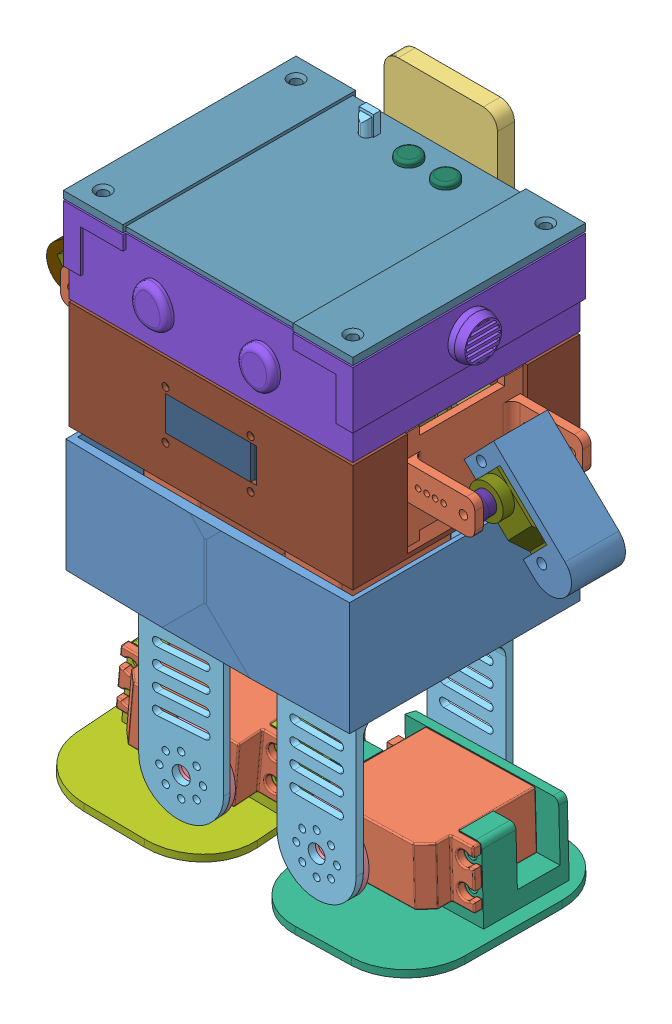
SolidWorks assembly Assemblage1, configuration Défaut. Lengths in mm.
Overall size (196.1 206.73 109.28).
35 component instances, 23 part files, 95 mates.
Components (placement in the parent):
- BodyBase-1: BodyBase [Défaut] at (-19.3328 -12.673 140) size (100 40 82)
- ServoS1213-1: ServoS1213 [Défaut] at (15.6672 25.827 129) x (0 0 -1) z (0 1 0) size (55 20 44)
- ServoS1213-2: ServoS1213 [Défaut] at (65.4301 25.827 129.0817) x (0.005444 0 -0.999985) z (0 1 0) size (55 20 44)
- LSM303D-1: LSM303D [Défaut] at (37.1672 -5.173 110) x (0 0 -1) z (0 1 0) size (21 13 13)
- PalonnierS1213-1: PalonnierS1213 [Défaut] at (5.6672 -20.173 100) x (0.070882 0 0.997485) z (-0.997485 0 0.070882) size (28 6 28)
- PalonnierS1213-2: PalonnierS1213 [Défaut] at (55.5882 -20.173 100.0277) x (0.710492 0 -0.703705) z (0.703705 0 0.710492) size (28 6 28)
- Bracket-1: Bracket [Défaut] at (69.72 -20.173 72.5952) x (-0.004799 0 0.999988) z (0.999988 0 0.004799) size (55 62.5 28)
- Bracket-2: Bracket [Défaut] at (17.6827 -20.173 71.5768) x (0.070882 0 0.997485) z (0.997485 0 -0.070882) size (55 62.5 28)
- Pied-1: Pied [Défaut] at (38.2903 -87.6714 63.4443) x (-0.004799 0 0.999988) z (-0.999594 -0.028092 -0.004797) size (74 28.5 60)
- ServoS1213-3: ServoS1213 [Défaut] at (84.9581 -77.8544 79.1684) x (-0.999594 -0.028092 -0.004797) z (0.004799 0 -0.999988) size (55 20 44)
- ServoS1213-4: ServoS1213 [Défaut] at (-23.7938 -56.2397 81.0406) x (0.993861 -0.085163 -0.070624) z (-0.070882 0 -0.997485) size (55 20 44)
- PalonnierS1213-3: PalonnierS1213 [Défaut] at (7.4392 -68.673 124.9371) x (0.705328 -0.707107 -0.050121) z (0.705328 0.707107 -0.050121) size (28 6 28)
- PalonnierS1213-4: PalonnierS1213 [Défaut] at (55.4682 -68.673 125.0274) x (0.999988 0 0.004799) z (0 1 0) size (28 6 28)
- Pied - Copie-1: Pied - Copie [Défaut] at (-40.2337 -83.529 66.6697) x (0.070882 0 0.997485) z (-0.993861 0.085163 0.070624) size (74 28.5 60)
- BodyMiddle-1: BodyMiddle [Défaut] at (-19.3328 69.5099 140) size (112 31.5 84)
- SocleBat-1: SocleBat [Défaut] at (-12.8328 70.5099 100) size (70 21 25)
- SocleBat-2: SocleBat [Défaut] at (-12.8328 70.5099 127) size (70 21 25)
- Ecran-1: Ecran [Défaut] at (12.6672 40.5959 135.5) x (1 0 0) z (0 -1 0) size (34 4.5 21)
- BodyTop-1: BodyTop [Défaut] at (-19.3328 30.5959 140) size (100 39.5 80)
- Teensy-bras-corps-base-X4-1: Teensy-bras-corps-base-X4 [Défaut] at (44.1672 32.0959 100.4183) x (0 0 1) z (0 1 0) size (45 57 25)
- PololuMicroMeastro-1: PololuMicroMeastro [Défaut] at (0.8991 32.0959 88.8193) x (0 0 -1) z (0 1 0) size (32.11 21.5 9.5)
- Couvercle-1: Couvercle [Défaut] at (-20.3328 100.1095 140) size (102 4 82)
- AttacheP-1: AttacheP [Défaut] at (43.161 101.6095 69.7544) x (0.425281 0 0.905062) z (-0.905062 0 0.425281) size (20 5.2 8)
- AttacheP-3: AttacheP [Défaut] at (29.9227 101.6095 69.5261) x (-0.997758 0 0.066931) z (-0.066931 0 -0.997758) size (20 5.2 8)
- ServoS1123-1: ServoS1123 [Défaut] at (-29.9448 51.815 86) x (-0.805744 -0.592264 0) z (0 0 -1) size (33 12 29)
- ServoS1123-2: ServoS1123 [Défaut] at (99.5187 61.5799 86) x (0.719374 -0.694623 0) z (0 0 -1) size (33 12 29)
- PalonnierS1123-1: PalonnierS1123 [Défaut] at (-38.3328 53.0959 117) x (1 0 0) z (0 1 0) size (22.5 5 8)
- PalonnierS1123-2: PalonnierS1123 [Défaut] at (99.6672 53.0959 117) x (-1 0 0) z (0 -1 0) size (22.5 5 8)
- MainD-1: MainD [Défaut] at (-53.3113 34.6394 83) x (0.805744 0.592264 0) z (0.592264 -0.805744 0) size (42.5 22 15)
- MainG-2: MainG [Défaut] at (86.867 57.1152 88) x (0.719374 -0.694623 0) z (-0.694623 -0.719374 0) size (42.5 22 15)
- epaule-1: epaule [Défaut] at (-14.8328 32.0959 75.5) x (0 0 1) z (-1 0 0) size (48 35 27.5)
- epaule-2: epaule [Défaut] at (76.1672 32.0959 123.5) x (0 0 -1) z (1 0 0) size (48 35 27.5)
- telecommande-1: telecommande [Défaut] at (48.6672 33.0959 51) x (0 1 0) z (0 0 1) size (85 40 7)
- sac-1: sac [Défaut] at (55.6672 30.0959 48) x (0 0 1) z (0 -1 0) size (31.28 50.4 43.75)
- ReceptIR-1: ReceptIR [Défaut] at (12.1672 101.6095 66.75) x (1 0 0) z (0 -1 0) size (5 4.5 30)
Mates (geometry in assembly coordinates):
- Coaxiale1: concentric aligned: circle of BodyBase-1; circle of ServoS1213-2
- Coïncidente2: coincident anti-aligned: plane of BodyBase-1 through (-19.3328 -4.173 140) normal (0 1 0); plane of ServoS1213-2 through (65.686 -4.173 82.0824) normal (0 -1 0)
- Coaxiale5: concentric anti-aligned: circle of BodyBase-1; circle of ServoS1213-2
- Coaxiale6: concentric aligned: circle of BodyBase-1; circle of ServoS1213-1
- Coïncidente3: coincident anti-aligned: plane of BodyBase-1 through (-19.3328 -4.173 140) normal (0 1 0); plane of ServoS1213-1 through (15.6672 -4.173 82) normal (0 -1 0)
- Coaxiale9: concentric aligned: circle of BodyBase-1; circle of ServoS1213-1
- Coïncidente4: coincident anti-aligned: plane of BodyBase-1 through (-19.3328 -5.173 140) normal (0 1 0); plane of LSM303D-1 through (37.1672 -5.173 110) normal (0 -1 0)
- Coïncidente5: coincident aligned: cylinder of BodyBase-1 through (34.6672 -19.173 107.5) axis (0 1 0) radius 1.25; circle of LSM303D-1
- Parallèle1: parallel anti-aligned: plane of BodyBase-1 through (37.1672 -5.173 94) normal (-1 0 0); plane of LSM303D-1 through (37.1672 -3.173 110) normal (1 0 0)
- Coaxiale10: concentric anti-aligned: circle of ServoS1213-1; circle of PalonnierS1213-1
- Coaxiale12: concentric anti-aligned: circle of ServoS1213-2; circle of PalonnierS1213-2
- Coïncidente7: coincident anti-aligned: plane of ServoS1213-2 through (55.5882 -18.173 100.0277) normal (0 -1 0); plane of PalonnierS1213-2 through (55.5882 -18.173 100.0277) normal (0 1 0)
- Coïncidente8: coincident anti-aligned: plane of ServoS1213-1 through (5.6672 -18.173 100) normal (0 -1 0); circle of PalonnierS1213-1
- Coaxiale13: concentric anti-aligned: circle of PalonnierS1213-1; circle of Bracket-2
- Coïncidente9: coincident anti-aligned: plane of PalonnierS1213-1 through (5.6672 -20.173 100) normal (0 -1 0); plane of Bracket-2 through (17.6827 -20.173 71.5768) normal (0 1 0)
- Coaxiale14: concentric anti-aligned: circle of PalonnierS1213-1; circle of Bracket-2
- Coïncidente10: coincident anti-aligned: plane of PalonnierS1213-2 through (55.5882 -20.173 100.0277) normal (0 -1 0); plane of Bracket-1 through (69.72 -20.173 72.5952) normal (0 1 0)
- Coaxiale15: concentric anti-aligned: circle of PalonnierS1213-2; circle of Bracket-1
- Coaxiale16: concentric anti-aligned: circle of PalonnierS1213-2; circle of Bracket-1
- Coaxiale17: concentric aligned: circle of Pied-1; cylinder of ServoS1213-3 through (88.9293 -62.734 101.1877) axis (-0.004799 0 0.999988) radius 2.5
- Coaxiale18: concentric aligned: circle of Pied-1; cylinder of ServoS1213-3 through (41.2297 -74.0784 100.9588) axis (-0.004799 0 0.999988) radius 2.5
- Coïncidente11: coincident anti-aligned: plane of Pied-1 through (92.8253 -77.6297 106.2065) normal (-0.004799 0 0.999988); plane of ServoS1213-3 through (37.8476 -79.1747 105.9426) normal (0.004799 0 -0.999988)
- Coaxiale19: concentric aligned: cylinder of ServoS1213-3 through (55.4778 -68.673 123.0275) axis (0.004799 0 -0.999988) radius 3; cylinder of PalonnierS1213-4 through (55.4778 -68.673 123.0275) axis (0.004799 0 -0.999988) radius 3.0436
- Coïncidente12: coincident anti-aligned: plane of ServoS1213-3 through (55.4778 -68.673 123.0275) normal (-0.004799 0 0.999988); plane of PalonnierS1213-4 through (55.4778 -68.673 123.0275) normal (0.004799 0 -0.999988)
- Coaxiale20: concentric aligned: circle of Bracket-1; circle of PalonnierS1213-4
- Coaxiale21: concentric anti-aligned: circle of Bracket-1; circle of PalonnierS1213-4
- Coïncidente14: coincident anti-aligned: plane of Bracket-1 through (41.4684 -82.673 124.9602) normal (0.004799 0 -0.999988); plane of PalonnierS1213-4 through (55.4682 -68.673 125.0274) normal (-0.004799 0 0.999988)
- Coaxiale22: concentric anti-aligned: circle of Bracket-1; circle of Pied-1
- Coaxiale23: concentric anti-aligned: circle of ServoS1213-4; circle of Pied - Copie-1
- Coaxiale24: concentric aligned: circle of ServoS1213-4; circle of Pied - Copie-1
- Coïncidente15: coincident anti-aligned: plane of ServoS1213-4 through (24.8315 -60.2423 104.6533) normal (-0.070882 0 -0.997485); plane of Pied - Copie-1 through (23.1325 -80.1696 104.774) normal (0.070882 0 0.997485)
- Coaxiale25: concentric aligned: cylinder of Bracket-2 through (3.7179 -68.673 72.5692) axis (0.070882 0 0.997485) radius 3; cylinder of Pied - Copie-1 through (3.6116 -68.673 71.0729) axis (0.070882 0 0.997485) radius 2.95
- Coaxiale26: concentric aligned: cylinder of ServoS1213-4 through (7.2975 -68.673 122.9421) axis (-0.070882 0 -0.997485) radius 3; cylinder of PalonnierS1213-3 through (7.2975 -68.673 122.9421) axis (-0.070882 0 -0.997485) radius 3.0436
- Coïncidente16: coincident anti-aligned: plane of ServoS1213-4 through (7.2975 -68.673 122.9421) normal (0.070882 0 0.997485); plane of PalonnierS1213-3 through (7.2975 -68.673 122.9421) normal (-0.070882 0 -0.997485)
- Coaxiale29: concentric anti-aligned: circle of Bracket-2; circle of PalonnierS1213-3
- Coaxiale30: concentric anti-aligned: circle of Bracket-2; circle of PalonnierS1213-3
- Coïncidente22: coincident anti-aligned: plane of Bracket-2 through (-6.5256 -82.673 125.9295) normal (-0.070882 0 -0.997485); plane of PalonnierS1213-3 through (7.4392 -68.673 124.9371) normal (0.070882 0 0.997485)
- Coaxiale31: concentric aligned: circle of Pied-1; cylinder of ServoS1213-3 through (40.9488 -64.0823 100.9575) axis (-0.004799 0 0.999988) radius 2.5
- Coaxiale32: concentric aligned: circle of Pied-1; circle of ServoS1213-3
- Coïncidente24: coincident anti-aligned: circle of BodyBase-1; cylinder of BodyMiddle-1 through (74.6672 64.5099 134) axis (0 1 0) radius 1.75
- Coaxiale33: concentric aligned: cylinder of BodyBase-1 through (-13.3328 -19.173 66) axis (0 1 0) radius 1.75; cylinder of BodyMiddle-1 through (-13.3328 64.5099 66) axis (0 1 0) radius 1.75
- Coïncidente28: coincident anti-aligned: plane of BodyMiddle-1 through (-19.3328 70.5099 140) normal (0 1 0); plane of SocleBat-2 through (-12.8328 70.5099 127) normal (0 -1 0)
- Coïncidente29: coincident anti-aligned: plane of BodyMiddle-1 through (-19.3328 70.5099 140) normal (0 1 0); plane of SocleBat-1 through (-12.8328 70.5099 100) normal (0 -1 0)
- Coïncidente30: coincident anti-aligned: plane of BodyMiddle-1 through (57.1672 70.5099 107) normal (-1 0 0); plane of SocleBat-2 through (57.1672 91.5099 127) normal (1 0 0)
- Coïncidente32: coincident anti-aligned: plane of BodyMiddle-1 through (57.1672 70.5099 80) normal (-1 0 0); plane of SocleBat-1 through (57.1672 91.5099 100) normal (1 0 0)
- Coïncidente33: coincident anti-aligned: plane of BodyMiddle-1 through (57.1672 70.5099 100) normal (0 0 -1); plane of SocleBat-1 through (-12.8328 91.5099 100) normal (0 0 1)
- Coaxiale36: concentric anti-aligned: cylinder of BodyMiddle-1 through (-13.3328 64.5099 66) axis (0 1 0) radius 1.75; cylinder of BodyTop-1 through (-13.3328 32.0959 66) axis (0 -1 0) radius 1.75
- Coaxiale37: concentric anti-aligned: cylinder of BodyMiddle-1 through (74.6672 64.5099 134) axis (0 1 0) radius 1.75; cylinder of BodyTop-1 through (74.6672 32.0959 134) axis (0 -1 0) radius 1.75
- Coïncidente36: coincident anti-aligned: plane of Ecran-1 through (12.6672 40.5959 138.5) normal (0 0 1); plane of BodyTop-1 through (-17.8328 68.5959 138.5) normal (0 0 -1)
- Coaxiale44: concentric aligned: cylinder of Ecran-1 through (44.6672 59.5959 133.5) axis (0 0 1) radius 1.25; cylinder of BodyTop-1 through (44.6672 59.5959 135) axis (0 0 1) radius 1.25
- Coaxiale45: concentric aligned: cylinder of Ecran-1 through (14.6672 42.5959 133.5) axis (0 0 1) radius 1.25; cylinder of BodyTop-1 through (14.6672 42.5959 135) axis (0 0 1) radius 1.25
- Parallèle6: parallel anti-aligned: plane of Couvercle-1 through (-20.3328 101.6095 140) normal (0 1 0); plane of AttacheP-3 through (29.9227 101.6095 69.5261) normal (0 -1 0)
- Parallèle7: parallel anti-aligned: plane of Couvercle-1 through (-20.3328 101.6095 140) normal (0 1 0); plane of AttacheP-1 through (43.161 101.6095 69.7544) normal (0 -1 0)
- Coïncidente45: coincident: circle of Couvercle-1; point of AttacheP-3
- Coïncidente46: coincident: circle of Couvercle-1; point of AttacheP-1
- Coaxiale50: concentric anti-aligned: cylinder of BodyTop-1 through (74.6672 32.0959 134) axis (0 -1 0) radius 1.75; cylinder of Couvercle-1 through (74.6672 96.6095 134) axis (0 1 0) radius 1.75
- Coaxiale51: concentric anti-aligned: cylinder of BodyTop-1 through (-13.3328 32.0959 66) axis (0 -1 0) radius 1.75; cylinder of Couvercle-1 through (-13.3328 96.6095 66) axis (0 1 0) radius 1.75
- Coaxiale52: concentric aligned: cylinder of BodyTop-1 through (68.6672 32.0959 113.9183) axis (0 -1 0) radius 1.75; cylinder of Teensy-bras-corps-base-X4-1 through (68.6672 33.6959 113.9183) axis (0 -1 0) radius 1.6
- Coaxiale53: concentric aligned: cylinder of BodyTop-1 through (19.6672 32.0959 113.9183) axis (0 -1 0) radius 1.75; cylinder of Teensy-bras-corps-base-X4-1 through (19.6672 33.6959 113.9183) axis (0 -1 0) radius 1.6
- Coïncidente47: coincident anti-aligned: plane of BodyTop-1 through (-19.3328 32.0959 140) normal (0 1 0); plane of Teensy-bras-corps-base-X4-1 through (44.1672 32.0959 100.4183) normal (0 -1 0)
- Coaxiale54: concentric aligned: cylinder of BodyTop-1 through (9.3872 32.0959 102.15) axis (0 -1 0) radius 1.25; cylinder of PololuMicroMeastro-1 through (9.3872 33.5959 102.15) axis (0 -1 0) radius 1.25
- Parallèle8: parallel aligned: cylinder of BodyTop-1 through (-7.3328 32.0959 87.64) axis (0 -1 0) radius 1.25; cylinder of PololuMicroMeastro-1 through (-7.3367 33.5959 87.6427) axis (0 -1 0) radius 1.25
- Parallèle10: parallel anti-aligned: plane of BodyTop-1 through (-17.8328 68.5959 61.5) normal (1 0 0); plane of PololuMicroMeastro-1 through (-9.8509 33.5959 88.8193) normal (-1 0 0)
- Coïncidente50: coincident anti-aligned: plane of BodyTop-1 through (-19.3328 32.0959 140) normal (0 1 0); plane of PololuMicroMeastro-1 through (0.8991 32.0959 88.8193) normal (0 -1 0)
- Coaxiale59: concentric anti-aligned: cylinder of ServoS1123-1 through (-38.3328 53.0959 115) axis (0 0 -1) radius 2; cylinder of PalonnierS1123-1 through (-38.3328 53.0959 112) axis (0 0 1) radius 2
- Coïncidente51: coincident anti-aligned: plane of ServoS1123-1 through (-38.3328 53.0959 115) normal (0 0 1); plane of PalonnierS1123-1 through (-38.3328 53.0959 115) normal (0 0 -1)
- Coaxiale60: concentric anti-aligned: cylinder of ServoS1123-2 through (99.6672 53.0959 115) axis (0 0 -1) radius 2; cylinder of PalonnierS1123-2 through (99.6672 53.0959 112) axis (0 0 1) radius 2
- Coïncidente52: coincident anti-aligned: plane of ServoS1123-2 through (99.6672 53.0959 115) normal (0 0 1); plane of PalonnierS1123-2 through (99.6672 53.0959 115) normal (0 0 -1)
- Coaxiale65: concentric aligned: cylinder of ServoS1123-1 through (-30.8394 58.604 99) axis (0 0 1) radius 1.75; cylinder of MainD-1 through (-30.8394 58.604 90) axis (0 0 1) radius 1.75
- Coaxiale68: concentric aligned: cylinder of ServoS1123-1 through (-54.6894 41.073 99) axis (0 0 1) radius 1.75; cylinder of MainD-1 through (-54.6894 41.073 90) axis (0 0 1) radius 1.75
- Coïncidente55: coincident anti-aligned: plane of ServoS1123-1 through (-52.5056 35.2317 102) normal (0 0 -1); plane of MainD-1 through (-57.7533 40.6825 102) normal (0 0 1)
- Coaxiale72: concentric aligned: cylinder of ServoS1123-2 through (114.2705 38.9951 99) axis (0 0 1) radius 1.75; cylinder of MainG-2 through (114.2705 38.9951 95) axis (0 0 1) radius 1.75
- Coaxiale73: concentric aligned: cylinder of ServoS1123-2 through (92.977 59.5559 99) axis (0 0 1) radius 1.75; cylinder of MainG-2 through (92.977 59.5559 95) axis (0 0 1) radius 1.75
- Coïncidente56: coincident anti-aligned: plane of ServoS1123-2 through (119.6611 42.1305 104) normal (0 0 1); plane of MainG-2 through (99.5187 61.5799 104) normal (0 0 -1)
- Parallèle11: parallel anti-aligned: plane of BodyTop-1 through (-17.8328 68.5959 123.5) normal (0 0 -1); plane of epaule-1 through (-17.3328 32.0959 123.5) normal (0 0 1)
- Coïncidente58: coincident anti-aligned: plane of BodyTop-1 through (-19.3328 32.0959 140) normal (0 1 0); plane of epaule-1 through (-17.3328 32.0959 75.5) normal (0 -1 0)
- Coïncidente59: coincident anti-aligned: line of BodyTop-1 through (-14.8328 67.0959 123.5) axis (0 -1 0); line of epaule-1 through (-14.8328 32.0959 123.5) axis (0 1 0)
- Coaxiale74: concentric aligned: cylinder of PalonnierS1123-1 through (-22.3328 53.0959 115) axis (0 0 1) radius 0.75; cylinder of epaule-1 through (-22.3328 53.0959 70) axis (0 0 1) radius 1
- Coaxiale75: concentric aligned: cylinder of PalonnierS1123-1 through (-31.3328 53.0959 115) axis (0 0 1) radius 0.75; cylinder of epaule-1 through (-31.3328 53.0959 70) axis (0 0 1) radius 1
- Coïncidente60: coincident anti-aligned: plane of PalonnierS1123-1 through (-38.3328 53.0959 117) normal (0 0 1); plane of epaule-1 through (-42.3328 59.0959 117) normal (0 0 -1)
- Coïncidente61: coincident anti-aligned: plane of BodyTop-1 through (79.1672 68.5959 75.5) normal (0 0 1); plane of epaule-2 through (78.6672 32.0959 75.5) normal (0 0 -1)
- Coïncidente62: coincident anti-aligned: plane of BodyTop-1 through (-19.3328 32.0959 140) normal (0 1 0); plane of epaule-2 through (78.6672 32.0959 123.5) normal (0 -1 0)
- Coïncidente63: coincident anti-aligned: line of BodyTop-1 through (76.1672 67.0959 75.5) axis (0 -1 0); line of epaule-2 through (76.1672 32.0959 75.5) axis (0 1 0)
- Coaxiale76: concentric anti-aligned: cylinder of PalonnierS1123-2 through (92.6672 53.0959 115) axis (0 0 1) radius 0.75; cylinder of epaule-2 through (92.6672 53.0959 129) axis (0 0 -1) radius 1
- Coaxiale77: concentric anti-aligned: cylinder of PalonnierS1123-2 through (83.6672 53.0959 115) axis (0 0 1) radius 0.75; cylinder of epaule-2 through (83.6672 53.0959 129) axis (0 0 -1) radius 1
- Coïncidente64: coincident anti-aligned: plane of PalonnierS1123-2 through (99.6672 53.0959 117) normal (0 0 1); plane of epaule-2 through (103.6672 59.0959 117) normal (0 0 -1)
- Coïncidente66: coincident anti-aligned: plane of telecommande-1 through (48.6672 33.0959 57) normal (0 -1 0); plane of sac-1 through (5.6672 33.0959 48) normal (0 1 0)
- Coïncidente67: coincident anti-aligned: plane of telecommande-1 through (48.6672 33.0959 57) normal (0 0 1); plane of sac-1 through (5.6672 30.0959 57) normal (0 0 -1)
- Coïncidente69: coincident aligned: line of telecommande-1 through (13.6672 33.0959 57) axis (1 0 0); line of sac-1 through (8.6672 33.0959 57) axis (1 0 0)
- Coïncidente70: coincident anti-aligned: plane of telecommande-1 through (8.6672 33.0959 57) normal (-1 0 0); plane of sac-1 through (8.6672 48.0686 38.9077) normal (1 0 0)
- Coïncidente72: coincident anti-aligned: plane of BodyTop-1 through (-19.3328 32.0959 60) normal (0 0 -1); plane of sac-1 through (5.6672 30.0959 60) normal (0 0 1)
- Coïncidente73: coincident anti-aligned: plane of BodyTop-1 through (42.6672 64.0959 51.5) normal (0 1 0); plane of sac-1 through (42.6672 64.0959 65) normal (0 -1 0)
- Coïncidente75: coincident anti-aligned: plane of BodyTop-1 through (18.6672 68.5959 51.5) normal (-1 0 0); plane of sac-1 through (18.6672 67.0959 65) normal (1 0 0)
- Coïncidente76: coincident anti-aligned: circle of Couvercle-1; plane of ReceptIR-1 through (12.1672 101.6095 69.25) normal (0 -1 0)
- Coaxiale79: concentric aligned: cylinder of Couvercle-1 through (14.6672 96.6095 68) axis (0 1 0) radius 2; cylinder of ReceptIR-1 through (14.6672 78.6095 68) axis (0 1 0) radius 0.25
